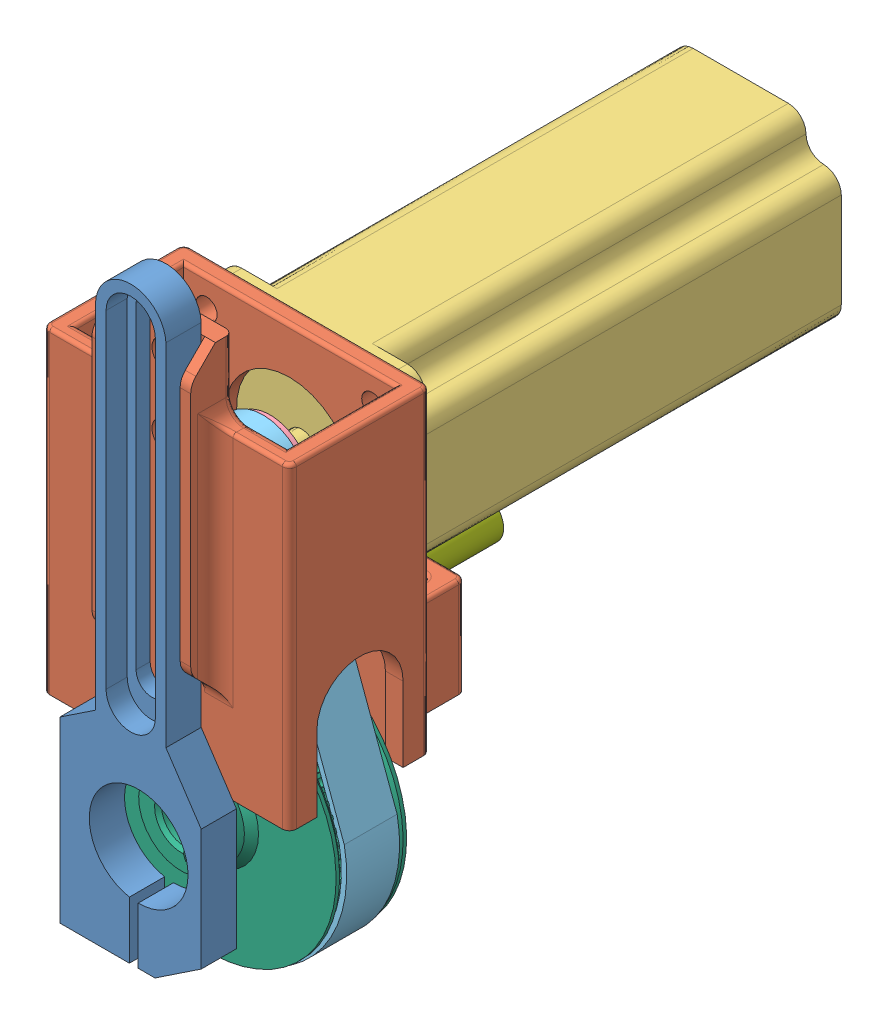
SolidWorks assembly motor_group, configuration Default. Lengths in mm.
Overall size (100.45 184.04 173).
7 component instances, 7 part files, 19 mates.
Components (placement in the parent):
- git-1: git [Default] at (41.6568 78.0701 173.203) size (40.11 167 10)
- x_motor_holder-1: x_motor_holder [Default] at (38.8716 68.16 177.7717) x (0 0 1) z (0 1 0) size (67 70 110)
- motor_57_123-1: motor_57_123 [Default] at (44.276 123.8958 10.203) size (57 57 151.5)
- sleeve15-1: sleeve15 [Default] at (39.4148 126.66 143.703) size (24 24 18)
- belt_15-1: belt_15 [Default] at (39.4148 126.66 145.703) x (-0.211093 -0.977466 0) z (0 0 1) size (120.5 73 15)
- sp_gear-1: sp_gear [Default] at (41.6568 53.5351 171.203) x (0.923728 0.383049 0) z (0 0 -1) size (72 72 30)
- big_sensor-1: big_sensor [Default] at (38.8716 83.16 82.9191) x (0.537657 -0.843164 0) z (0 0 1) size (19 19 60.5)
Mates (geometry in assembly coordinates):
- Coincident2: coincident anti-aligned: plane of git-1 through (39.4139 180.5351 173.203) normal (0 0 -1); plane of x_motor_holder-1 through (34.1272 158.16 173.203) normal (0 0 1)
- Coincident4: coincident anti-aligned: plane of x_motor_holder-1 through (74.4148 158.16 133.203) normal (0 0 -1); plane of motor_57_123-1 through (44.276 123.8958 133.203) normal (0 0 1)
- Concentric1: concentric aligned: cylinder of motor_57_123-1 through (39.4148 126.66 161.703) axis (0 0 -1) radius 4; cylinder of sleeve15-1 through (39.4148 126.66 161.703) axis (0 0 -1) radius 4
- Coincident7: coincident aligned: plane of motor_57_123-1 through (39.4148 126.66 161.703) normal (0 0 1); plane of sleeve15-1 through (39.4148 126.66 161.703) normal (0 0 1)
- Concentric2: concentric aligned: cylinder of sleeve15-1 through (39.4148 126.66 161.703) axis (0 0 -1) radius 12; cylinder of belt-1 through (22.9651 133.03 145.7358) axis (0 0 -1) radius 13
- Coincident8: coincident aligned: plane of sleeve15-1 through (39.4148 126.66 161.703) normal (0 0 1); plane of belt-1 through (22.9651 133.03 145.7358) normal (0 0 1)
- Concentric3: concentric aligned: cylinder of sleeve15-1 through (39.4148 126.66 161.703) axis (0 0 -1) radius 12; cylinder of belt_15-1 through (39.4148 126.66 160.703) axis (0 0 -1) radius 11.5
- Distance4: distance = 1 mm aligned: plane of belt_15-1 through (39.4148 126.66 160.703) normal (0 0 1); plane of sleeve15-1 through (39.4148 126.66 161.703) normal (0 0 1)
- Concentric4: concentric anti-aligned: cylinder of git-1 through (41.6568 53.5351 83.203) axis (0 0 1) radius 14; cylinder of belt_15-1 through (41.6568 53.5351 160.703) axis (0 0 -1) radius 35
- Concentric5: concentric aligned: cylinder of belt_15-1 through (41.6568 53.5351 160.703) axis (0 0 -1) radius 35; cylinder of sp_gear-1 through (41.6568 53.5351 160.203) axis (0 0 -1) radius 34.85
- Coincident10: coincident: plane of belt_15-1 through (39.4148 126.66 160.703) normal (0 0 1); plane of sp_gear-1 through (47.8093 42.4797 160.703) normal (0 0 1)
- Parallel1: parallel aligned: cylinder of x_motor_holder-1 through (39.4148 126.66 140.203) axis (0 0 -1) radius 18.5; cylinder of motor_57_123-1 through (39.4148 126.66 161.703) axis (0 0 -1) radius 4
- Distance6: distance = 1 mm: plane of x_motor_holder-1 through (28.4148 178.16 180.203) normal (1 0 0); plane of git-1 through (31.4885 3.53 183.203) normal (-1 0 0)
- Concentric8: concentric aligned: cylinder of x_motor_holder-1 through (39.4148 126.66 140.203) axis (0 0 -1) radius 18.5; cylinder of motor_57_123-1 through (39.4148 126.66 161.703) axis (0 0 -1) radius 4
- Concentric9: concentric anti-aligned: cylinder of x_motor_holder-1 through (38.8716 83.16 113.203) axis (0 0 1) radius 6.5; cylinder of big_sensor-1 through (38.8716 83.16 137.9191) axis (0 0 -1) radius 6
- Concentric10: concentric aligned: cylinder of git-1 through (41.6568 53.5351 83.203) axis (0 0 1) radius 14; cylinder of sp_gear-1 through (41.6568 53.5351 143.203) axis (0 0 1) radius 12
- Distance7: distance = 2 mm anti-aligned: plane of sp_gear-1 through (41.6568 53.5351 171.203) normal (0 0 1); plane of git-1 through (39.4139 180.5351 173.203) normal (0 0 -1)
- Parallel2: parallel aligned: plane of git-1 through (29.4148 180.6664 183.203) normal (-1 0 0); plane of x_motor_holder-1 through (4.4148 158.16 133.203) normal (-1 0 0)
- Distance8: distance = 1 mm anti-aligned: plane of x_motor_holder-1 through (28.4148 178.16 180.203) normal (1 0 0); plane of git-1 through (29.4148 180.6664 183.203) normal (-1 0 0)
